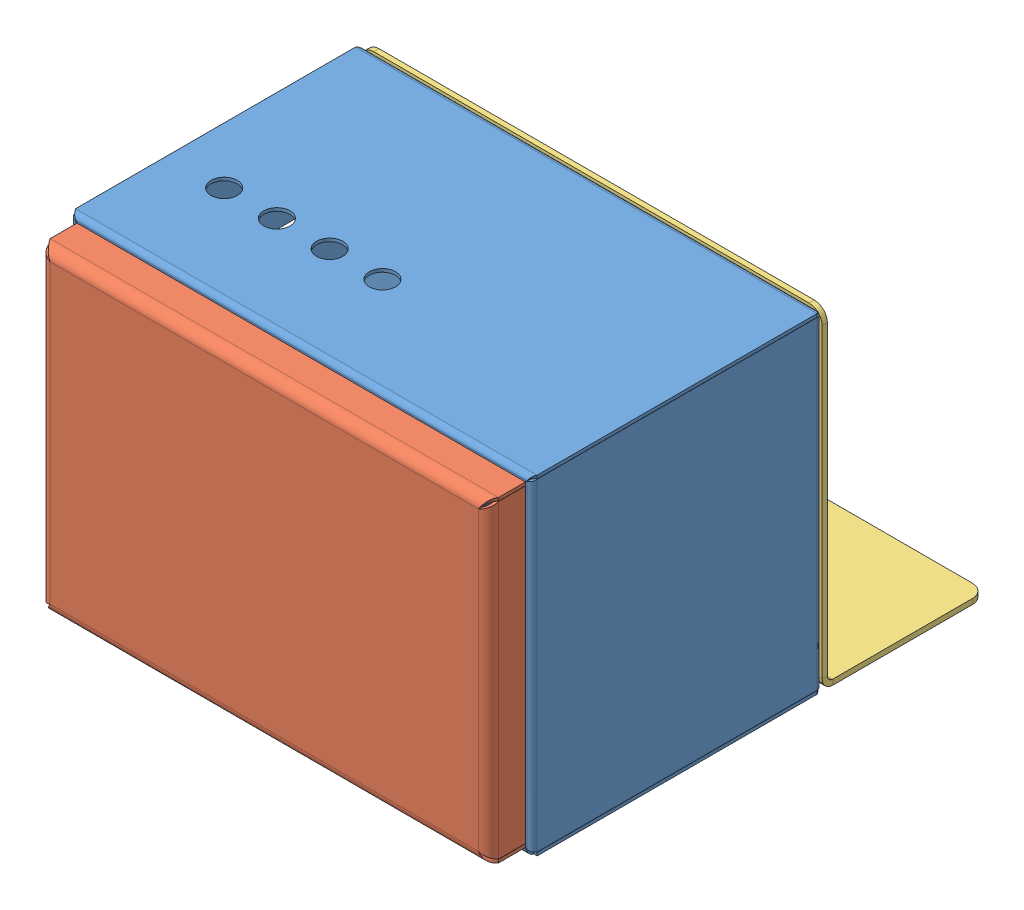
SolidWorks assembly Panel, configuration Default. Lengths in mm.
Overall size (175.31 185 186).
3 component instances, 3 part files, 6 mates.
Components (placement in the parent):
- Panel box-1: Panel box [Default] at (49.431 101.8756 74.052) size (175.31 125.01 123.8)
- Door-1: Door [Default] at (49.431 101.8756 198.052) x (-1 0 0) z (0 0 -1) size (170.3 120.01 14)
- Bracket-1: Bracket [Default] at (49.431 101.8756 74.052) x (-1 0 0) z (0 0 -1) size (175 185 62)
Mates (geometry in assembly coordinates):
- Distance7: distance = 2.5 mm aligned: plane of Door-1 through (134.431 101.8756 198.052) normal (1 0 0); plane of Panel box-1 through (136.931 101.8756 74.052) normal (1 0 0)
- Distance8: distance = 2.5 mm aligned: plane of Panel box-1 through (49.431 164.3756 74.052) normal (0 1 0); plane of Door-1 through (49.431 161.8756 198.052) normal (0 1 0)
- Coincident19: coincident anti-aligned: plane of Panel box-1 through (49.431 101.8756 184.052) normal (0 0 1); plane of Door-1 through (-35.569 161.8756 184.052) normal (0 0 -1)
- Concentric17: concentric anti-aligned: cylinder of Panel box-1 through (119.9944 147.439 197.853) axis (0 0 -1) radius 2.75; cylinder of Bracket-1 through (119.9944 147.439 72.052) axis (0 0 1) radius 2.75
- Concentric18: concentric anti-aligned: cylinder of Panel box-1 through (-21.1324 56.3122 197.853) axis (0 0 -1) radius 2.75; cylinder of Bracket-1 through (-21.1324 56.3122 72.052) axis (0 0 1) radius 2.75
- Coincident20: coincident anti-aligned: plane of Panel box-1 through (49.431 101.8756 74.052) normal (0 0 -1); plane of Bracket-1 through (49.431 101.8756 74.052) normal (0 0 1)
